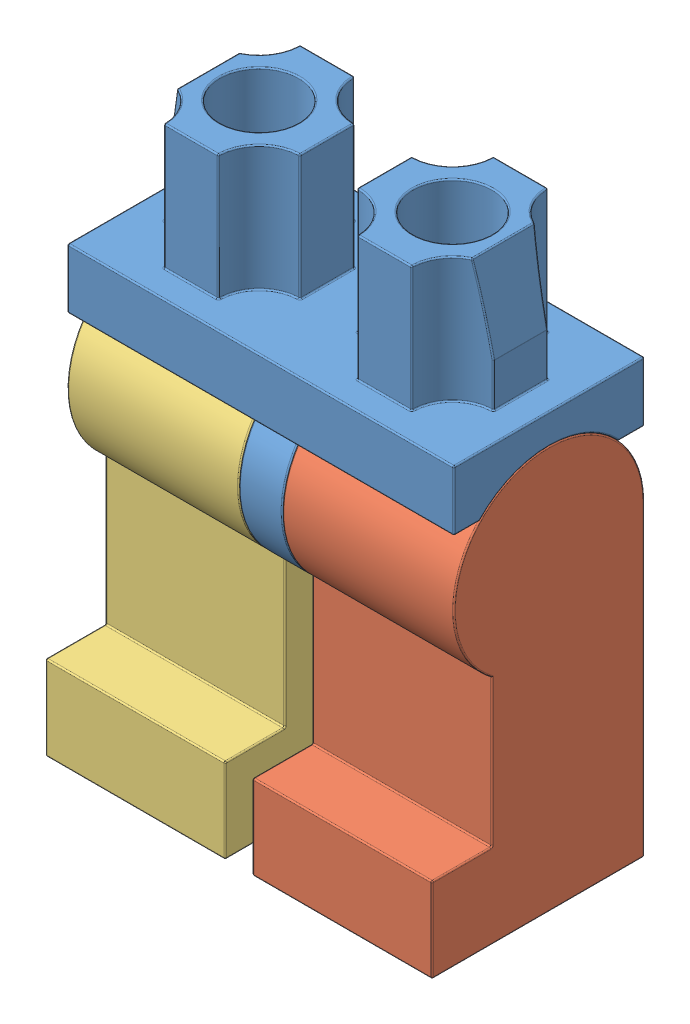
SolidWorks assembly Man, configuration Default. Lengths in mm.
Overall size (14.2 20.5 7.98).
3 component instances, 3 part files, 4 mates.
Components (placement in the parent):
- Base Leg Mid-1: Base Leg Mid [Default] at (-3.5924 -2.1836 1.4429) size (14.2 12.7 7)
- Base Leg Left-1: Base Leg Left [Default] at (-3.0924 -13.4836 -2.0571) x (1 0 0) z (0 -1 0) size (6.6 7.98 14.8)
- Base Leg Right-1: Base Leg Right [Default] at (-4.0924 -13.4836 -2.0571) x (1 0 0) z (0 -1 0) size (6.6 7.98 14.8)
Mates (geometry in assembly coordinates):
- Concentric1: concentric aligned: cylinder of Base Leg Mid-1; cylinder of Base Leg Right-1
- Concentric2: concentric aligned: cylinder of Base Leg Mid-1; cylinder of Base Leg Left-1
- Coincident1: coincident anti-aligned: plane of Base Leg Mid-1 through (-2.7924 -2.1836 1.4429) normal (1 0 0); plane of Base Leg Left-1 through (-2.7924 -2.1836 1.4429) normal (-1 0 0)
- Coincident2: coincident anti-aligned: plane of Base Leg Mid-1 through (-4.3924 -2.1836 1.4429) normal (-1 0 0); plane of Base Leg Right-1 through (-4.3924 -2.1836 1.4429) normal (1 0 0)
